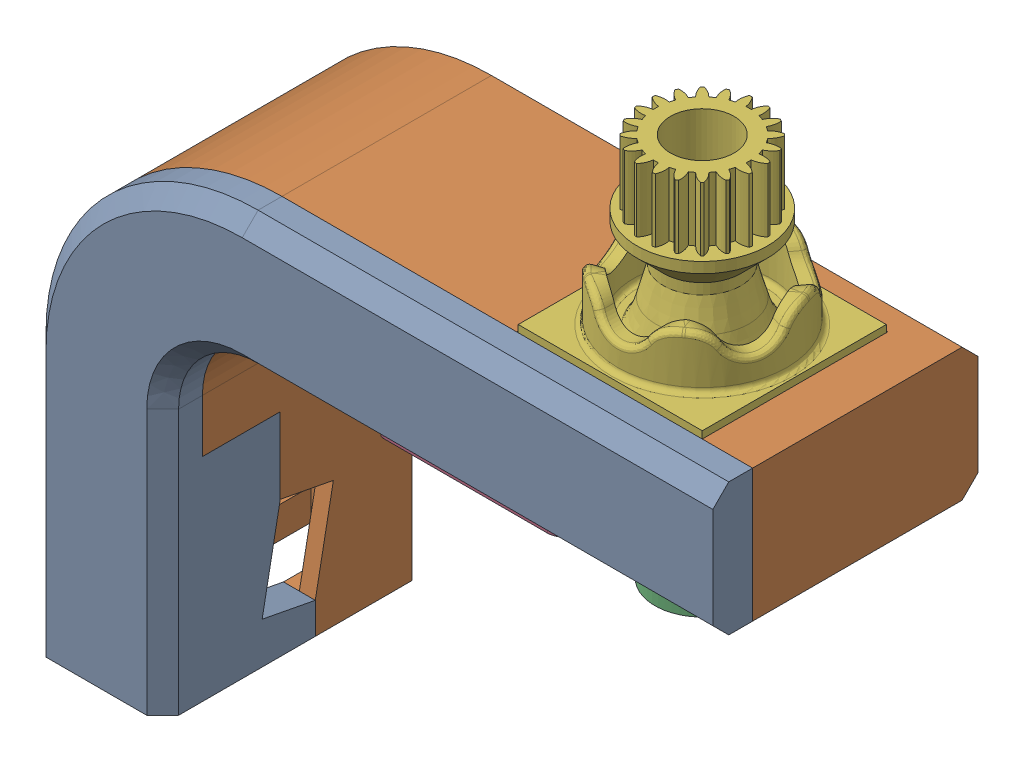
SolidWorks assembly Armature, configuration Default. Lengths in mm.
Overall size (128.75 122.2 46.5).
6 component instances, 6 part files, 12 mates.
Components (placement in the parent):
- lowerarmpart1-1: lowerarmpart1 [Default] at origin size (128.75 90 32.78) (hidden)
- lowerarmpart2-1: lowerarmpart2 [Default] at origin size (128.75 90 42.5)
- colorsensor-1: colorsensor [Default] at (0 69.7327 0) x (1 0 0) z (0 0 -1) size (41.7 10 23.8)
- colorsensormountingplate-1: colorsensormountingplate [Default] at (-44 75 0) x (-1 0 0) z (0 0 -1) size (35 5.27 34.4)
- 90592A075_Steel Hex Nut-1: 90592A075_Steel Hex Nut [90592A075] at (-39.8 68.93 -13) x (1 0 0) z (0 -1 0) size (4 4.59 1.6)
- rotatingjoint-1: rotatingjoint [Default] at (0 95.8 0) size (43 36.4 43)
Mates (geometry in assembly coordinates):
- Distance8: distance = 16.2202 mm aligned: plane of colorsensor-1 through (10.7798 68.1327 0) normal (1 0 0); plane of lowerarmpart2-1 through (27 0 25) normal (1 0 0)
- Distance9: distance = 13.1 mm aligned: plane of colorsensor-1 through (0 68.1327 -11.9) normal (0 0 -1); plane of lowerarmpart2-1 through (0 0 -25) normal (0 0 -1)
- Distance10: distance = 5.2673 mm anti-aligned: plane of colorsensor-1 through (0 69.7327 0) normal (0 1 0); plane of lowerarmpart2-1 through (0 75 25) normal (0 -1 0)
- Width1: width aligned: plane of colorsensormountingplate-1 through (-44 75 -17.2) normal (0 0 -1); plane of colorsensormountingplate-1 through (-44 75 17.2) normal (0 0 1); plane of colorsensor-1 through (0 68.1327 -11.9) normal (0 0 -1); plane of colorsensor-1 through (0 68.1327 11.9) normal (0 0 1)
- Coincident4: coincident anti-aligned: plane of lowerarmpart2-1 through (0 75 25) normal (0 -1 0); plane of colorsensormountingplate-1 through (-44 75 -17.2) normal (0 1 0)
- Coincident5: coincident aligned: plane of colorsensormountingplate-1 through (-44 75 -17.2) normal (-1 0 0); plane of lowerarmpart2-1 through (-44 9.999 -16.5) normal (-1 0 0)
- Concentric1: concentric anti-aligned: cylinder of colorsensormountingplate-1 through (-39.8 69.729 -13) axis (0 1 0) radius 1.2; cylinder of 90592A075_Steel Hex Nut-1 through (-39.8 69.73 -13) axis (0 -1 0) radius 1
- Coincident6: coincident anti-aligned: plane of colorsensormountingplate-1 through (-44 69.73 -17.2) normal (0 -1 0); plane of 90592A075_Steel Hex Nut-1 through (-39.8 69.73 -13) normal (0 1 0)
- Parallel3: parallel anti-aligned: plane of colorsensor-1 through (-30.9202 68.1327 0) normal (-1 0 0); plane of 90592A075_Steel Hex Nut-1 through (-37.8 68.13 -14.1547) normal (1 0 0)
- Coincident8: coincident aligned: plane of rotatingjoint-1 through (0 38.734 0) normal (0 0 1)
- Coincident9: coincident aligned: plane of rotatingjoint-1 through (0 38.734 0) normal (1 0 0)
- Coincident10: coincident anti-aligned: plane of lowerarmpart2-1 through (-21.6 98.5 21.6) normal (0 -1 0); plane of rotatingjoint-1 through (0 41.434 0) normal (0 1 0)
